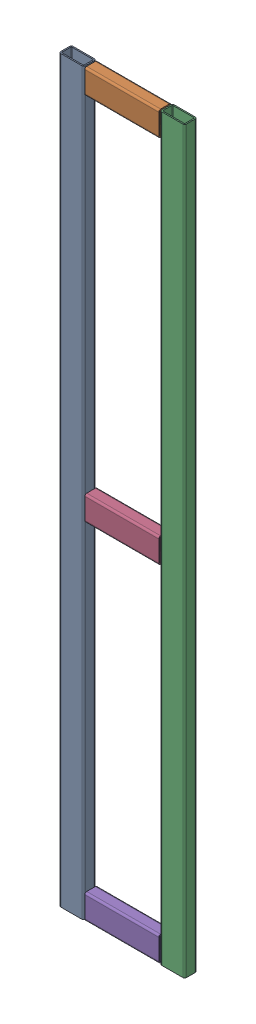
SolidWorks assembly Щит1, configuration По умолчанию. Lengths in mm.
Overall size (204 1200 20).
5 component instances, 2 part files, 12 mates.
Components (placement in the parent):
- Профиль2040-1: Профиль2040 [По умолчанию] at origin size (40 1200 20)
- Профиль2040200-1: Профиль2040200 [По умолчанию] at (162 1160 0) x (0 1 0) z (0 0 1) size (40 120 20)
- Профиль2040-2: Профиль2040 [По умолчанию] at (164 0 0) size (40 1200 20)
- Профиль2040200-2: Профиль2040200 [По умолчанию] at (162 560 0) x (0 1 0) z (0 0 1) size (40 120 20)
- Профиль2040200-3: Профиль2040200 [По умолчанию] at (162 0 0) x (0 1 0) z (0 0 1) size (40 120 20)
Mates (geometry in assembly coordinates):
- Совпадение1: coincident aligned: plane of Профиль2040-1 through (3 1200 0) normal (0 0 1); plane of Профиль2040200-1 through (42 1163 0) normal (0 0 1)
- Расстояние1: distance = 2 mm anti-aligned: plane of Профиль2040200-1 through (42 1197 -3) normal (-1 0 0); plane of Профиль2040-1 through (40 1200 -3) normal (1 0 0)
- Совпадение3: coincident aligned: plane of Профиль2040-1 through (37 1200 -3) normal (0 1 0); plane of Профиль2040200-1 through (42 1200 -3) normal (0 1 0)
- Совпадение4: coincident aligned: plane of Профиль2040200-1 through (42 1200 -3) normal (0 1 0); plane of Профиль2040-2 through (201 1200 -3) normal (0 1 0)
- Совпадение5: coincident aligned: plane of Профиль2040200-1 through (42 1163 0) normal (0 0 1); plane of Профиль2040-2 through (167 1200 0) normal (0 0 1)
- Расстояние2: distance = 2 mm anti-aligned: plane of Профиль2040200-1 through (162 1197 -3) normal (1 0 0); plane of Профиль2040-2 through (164 1200 -3) normal (-1 0 0)
- Совпадение7: coincident aligned: plane of Профиль2040200-1 through (42 1163 0) normal (0 0 1); plane of Профиль2040200-2 through (42 563 0) normal (0 0 1)
- Совпадение8: coincident aligned: plane of Профиль2040200-2 through (42 563 0) normal (0 0 1); plane of Профиль2040200-3 through (42 3 0) normal (0 0 1)
- Совпадение9: coincident aligned: plane of Профиль2040200-1 through (162 1197 -3) normal (1 0 0); plane of Профиль2040200-2 through (162 597 -3) normal (1 0 0)
- Совпадение10: coincident aligned: plane of Профиль2040200-2 through (162 597 -3) normal (1 0 0); plane of Профиль2040200-3 through (162 37 -3) normal (1 0 0)
- Совпадение11: coincident aligned: plane of Профиль2040-2 through (201 0 -3) normal (0 -1 0); plane of Профиль2040200-3 through (42 0 -3) normal (0 -1 0)
- Расстояние3: distance = 520 mm anti-aligned: plane of Профиль2040200-2 through (42 560 -3) normal (0 -1 0); plane of Профиль2040200-3 through (42 40 -3) normal (0 1 0)
